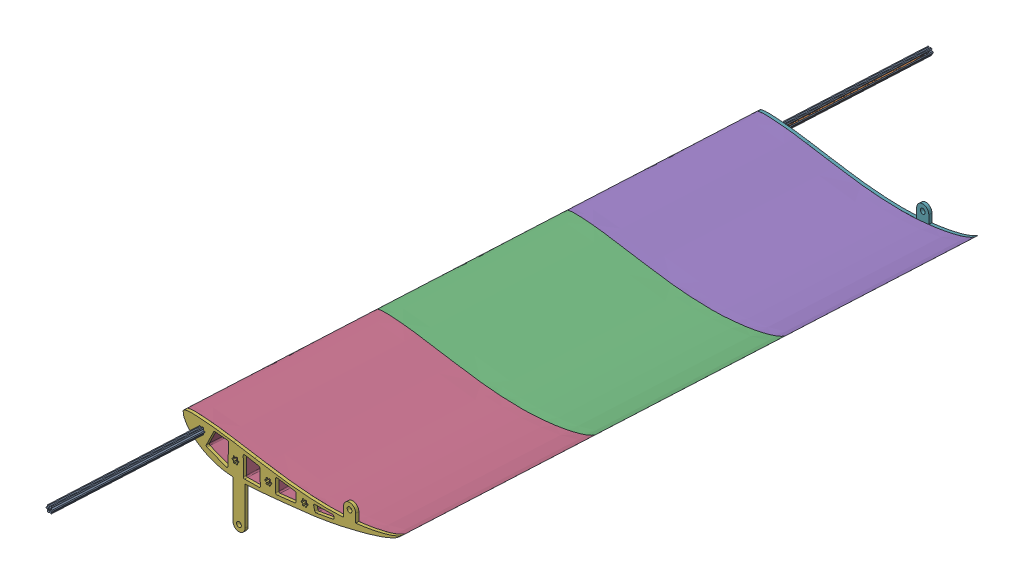
SolidWorks assembly Assem1Airfoil, configuration Default. Lengths in mm.
Overall size (490.69 206.67 1764.86).
6 component instances, 3 part files, 14 mates.
Components (placement in the parent):
- Churro-1: Churro [Default] at (-426.8629 461.9863 -1404.0738) x (0.999254 0.032402 0.020998) z (-0.021908 0.027985 0.999368) size (14.66 12.7 1765.3)
- AirfoilSectionSmall-2: AirfoilSectionSmall [Default] at (-460.9778 401.7892 -710.5484) x (0.999254 0.032402 0.020998) z (-0.021908 0.027985 0.999368) size (460.64 71.94 381)
- AirfoilSectionSmall-3: AirfoilSectionSmall [Default] at (-469.3246 412.4515 -329.7891) x (0.999254 0.032402 0.020998) z (-0.021908 0.027985 0.999368) size (460.64 71.94 381)
- AirfoilSectionSmall-4: AirfoilSectionSmall [Default] at (-452.631 391.1268 -1091.3077) x (0.999254 0.032402 0.020998) z (-0.021908 0.027985 0.999368) size (460.64 71.94 381)
- AirfoilStrutPlate-1: AirfoilStrutPlate [Default] at (-477.6714 423.1138 50.9702) x (0.999254 0.032402 0.020998) z (-0.021908 0.027985 0.999368) size (460.64 159.54 6.35)
- AirfoilStrutPlate-2: AirfoilStrutPlate [Default] at (-452.4919 390.9491 -1097.6537) x (0.999254 0.032402 0.020998) z (-0.021908 0.027985 0.999368) size (460.64 159.54 6.35)
Mates (geometry in assembly coordinates):
- Concentric2: concentric anti-aligned: cylinder of Churro-1 through (-433.8949 464.8828 -1073.9003) axis (0.021908 -0.027985 -0.999368) radius 1.5875; cylinder of AirfoilSectionSmall-3 through (-450.1712 485.6744 -331.4196) axis (-0.021908 0.027985 0.999368) radius 1.5875
- Coincident2: coincident aligned: cylinder of Churro-1 through (-434.2987 477.5712 -1074.2644) axis (0.021908 -0.027985 -0.999368) radius 1.5875; circle of AirfoilSectionSmall-3
- Concentric3: concentric anti-aligned: cylinder of Churro-1 through (-433.8949 464.8828 -1073.9003) axis (0.021908 -0.027985 -0.999368) radius 1.5875; cylinder of AirfoilSectionSmall-2 through (-441.8244 475.0121 -712.179) axis (-0.021908 0.027985 0.999368) radius 1.5875
- Coincident3: coincident aligned: cylinder of Churro-1 through (-434.2987 477.5712 -1074.2644) axis (0.021908 -0.027985 -0.999368) radius 1.5875; circle of AirfoilSectionSmall-2
- Concentric4: concentric anti-aligned: cylinder of Churro-1 through (-433.8949 464.8828 -1073.9003) axis (0.021908 -0.027985 -0.999368) radius 1.5875; cylinder of AirfoilSectionSmall-4 through (-433.4776 464.3497 -1092.9383) axis (-0.021908 0.027985 0.999368) radius 1.5875
- Coincident4: coincident aligned: cylinder of Churro-1 through (-434.2987 477.5712 -1074.2644) axis (0.021908 -0.027985 -0.999368) radius 1.5875; circle of AirfoilSectionSmall-4
- Coincident9: coincident anti-aligned: plane of AirfoilSectionSmall-2 through (-41.3855 510.4412 -323.152) normal (-0.021908 0.027985 0.999368); plane of AirfoilSectionSmall-3 through (-41.3855 510.4412 -323.152) normal (0.021908 -0.027985 -0.999368)
- Coincident10: coincident anti-aligned: plane of AirfoilSectionSmall-2 through (-33.0387 499.7789 -703.9113) normal (0.021908 -0.027985 -0.999368); plane of AirfoilSectionSmall-4 through (-33.0387 499.7789 -703.9113) normal (-0.021908 0.027985 0.999368)
- Coincident38: coincident anti-aligned: cylinder of Churro-1 through (-439.6929 474.2209 -1074.2889) axis (0.021908 -0.027985 -0.999368) radius 1.5875; circle of AirfoilStrutPlate-2
- Coincident41: coincident aligned: cylinder of Churro-1 through (-434.2987 477.5712 -1074.2644) axis (0.021908 -0.027985 -0.999368) radius 1.5875; circle of AirfoilStrutPlate-1
- Coincident42: coincident aligned: cylinder of Churro-1 through (-439.6929 474.2209 -1074.2889) axis (0.021908 -0.027985 -0.999368) radius 1.5875; circle of AirfoilStrutPlate-1
- Coincident45: coincident anti-aligned: plane of AirfoilSectionSmall-3 through (-49.7322 521.1036 57.6073) normal (-0.021908 0.027985 0.999368); plane of AirfoilStrutPlate-1 through (-181.1114 479.0254 55.9056) normal (0.021908 -0.027985 -0.999368)
- Coincident46: coincident anti-aligned: plane of AirfoilSectionSmall-4 through (-24.6919 489.1166 -1084.6706) normal (0.021908 -0.027985 -0.999368); plane of AirfoilStrutPlate-2 through (-156.071 447.0384 -1086.3723) normal (-0.021908 0.027985 0.999368)
- Distance1: distance = 304.8 mm aligned: plane of AirfoilStrutPlate-2 through (-155.9319 446.8607 -1092.7183) normal (0.021908 -0.027985 -0.999368); plane of Churro-1 through (-421.4687 465.3366 -1404.0493) normal (0.021908 -0.027985 -0.999368)
